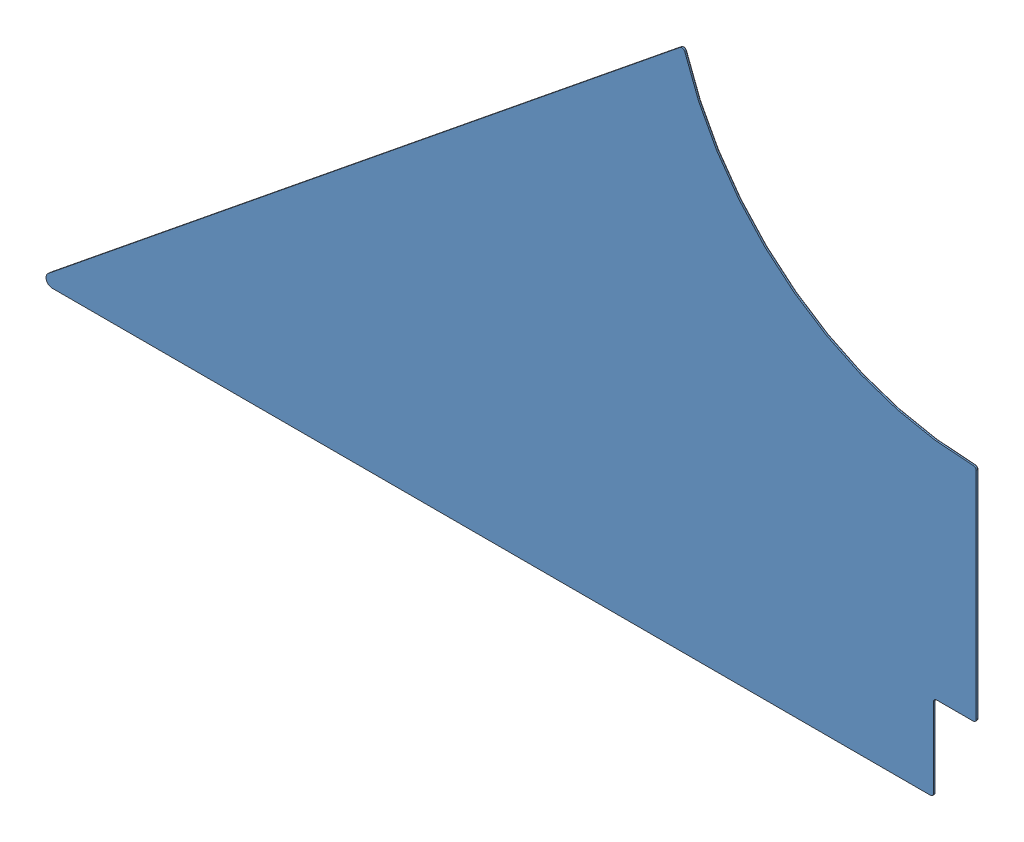
SolidWorks assembly GE-20018, configuration GE-20018-Blue. Lengths in mm.
Overall size (967.1 543.85 1.84).
2 component instances, 2 part files, 6 mates.
Components (placement in the parent):
- GE-20016-1: GE-20016 [Default] at (0 -253.903 -1.5875) size (967.1 543.85 1.59)
- GE-20018-Vinyl-1: GE-20018-Vinyl [GE-20018-Blue-Vinyl] at (0 -253.903 -3.175) size (967.1 543.85 0.25)
Mates (geometry in assembly coordinates):
- Coincident1: coincident aligned: plane of GE-20016-1 through (0 636.6845 0) normal (0 0 1)
- Coincident2: coincident anti-aligned: plane of GE-20016-1 through (-44.45 0 -1.5875) normal (0 -1 0)
- Coincident3: coincident aligned: plane of GE-20016-1 through (0 -253.903 -1.5875) normal (1 0 0)
- Coincident4: coincident anti-aligned: plane of GE-20016-1 through (0 636.6845 -1.5875) normal (0 0 -1); plane of GE-20018-Vinyl-1 through (0 636.6845 -1.5875) normal (0 0 1)
- Coincident5: coincident aligned: plane of GE-20016-1 through (0 -253.903 -1.5875) normal (1 0 0); plane of GE-20018-Vinyl-1 through (0 -253.903 -3.175) normal (1 0 0)
- Coincident6: coincident aligned: plane of GE-20016-1 through (-44.45 0 -1.5875) normal (0 -1 0); plane of GE-20018-Vinyl-1 through (-44.45 0 -3.175) normal (0 -1 0)
